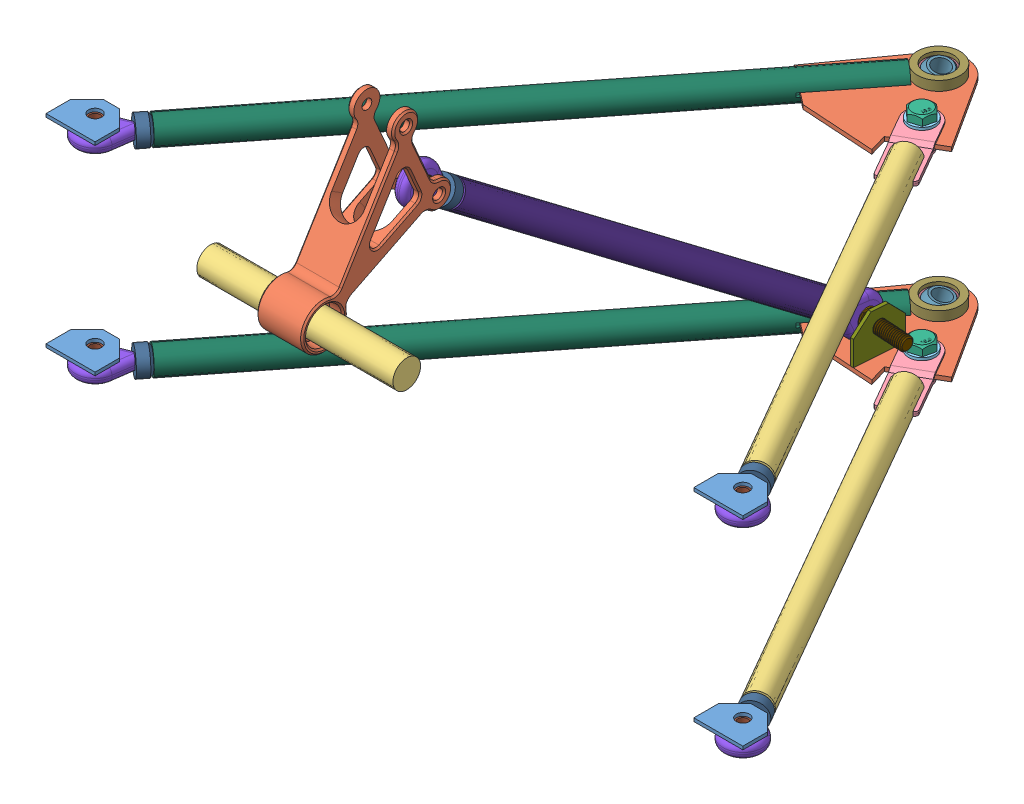
SolidWorks assembly Control Arms, Pushord, Bellcrank V2, configuration Default. Lengths in mm.
Overall size (449.35 294.9 454.01).
66 component instances, 21 part files, 26 mates.
Components (placement in the parent):
- frame connectors-10: frame connectors [Default] at (-357.6393 7.7366 39.1204) size (30 2 25)
- frame connectors-11: frame connectors [Default] at (38.6473 7.7366 39.1204) size (30 2 25)
- Upper Control Arm Assembly-1: Upper Control Arm Assembly [Default] at (-132.0035 -126.1112 -251.3303) x (0.997989 0.000512 0.063393) z (-0.063395 0.008067 0.997956) size (428.86 42.68 337.97) (flexible)
  - Front Control Arm Plate-1: Front Control Arm Plate [Default] at origin size (91 2.5 76.52)
  - Rear Upper Control Arm-2: Rear Upper Control Arm [Default] at (105.6055 0 154.4308) x (-0.554844 0 -0.831954) z (0.831954 0 -0.554844) size (250 16 16)
  - Control Arm Link Plate-1: Control Arm Link Plate [Default] at (31.8652 1.25 43.6848) x (-0.554844 0 -0.831954) z (0.831954 0 -0.554844) size (54.1 2.5 20)
  - Control Arm Link Plate-2: Control Arm Link Plate [Default] at (31.8652 -1.25 43.6848) x (-0.554844 0 -0.831954) z (-0.831954 0 0.554844) size (54.1 2.5 20)
  - plain washer normal grade a_iso-1: plain washer normal grade a_iso [Washer ISO 7089 - 8] at (22.4051 2.5 29.5) x (0 -1 0) z (0.774417 0 0.632675) size (1.6 16 16)
  - 94863A205_High-Strength Class 10.9 Steel Hex Head Screw-1: 94863A205_High-Strength Class 10.9 Steel Hex Head Screw [94863A205] at (22.4051 4.1 29.5) x (0.632675 0 -0.774417) z (0 1 0) size (13 16.35 25.89)
  - 94645A111_High-Strength Steel Nylon-Insert Locknut-1: 94645A111_High-Strength Steel Nylon-Insert Locknut [94645A111] at (22.4051 -6.5 29.5) x (-0.775761 0 -0.631027) z (-0.631027 0 0.775761) size (13 8 14.93)
  - Link Insert Assembly-1: Link Insert Assembly [Default] at (151.1806 41.9532 246.62) x (0.831954 0 -0.554844) z (0 -1 0) size (24 54 13.75) (flexible)
    - Link-1: Link [Default] at (13.2343 18.3157 41.9532) size (24 54 13.75)
    - Spherical Bearing Ball-1: Spherical Bearing Ball [Default] at (13.2343 47.8157 41.9532) x (0.00405 -0.006996 0.999967) z (0.475433 -0.879715 -0.00808) size (9 13.75 13.75)
  - Control Arm Insert-1: Control Arm Insert [Default] at (162.0573 0 239.0767) x (-0.831525 0.032128 0.554558) z (0.026729 0.999484 -0.017826) size (16 25 16)
  - 8mm Spehrical Bearing Insert-1: 8mm Spehrical Bearing Insert [Default] at (188.7245 6.4998 279.11) x (0.943262 0.002195 -0.332043) z (-0.33205 0.007779 -0.94323) size (11 9 11)
  - Spherical Bearing Seat-1: Spherical Bearing Seat [Default] at (0 -0.3 0) size (30 15.1 30)
  - Wide Spherical Bearing-1: Wide Spherical Bearing [Default] at (-7.3247 -16.3877 13.3464) x (1 0 0) z (0 1 0) size (28.86 28.32 19.03) (flexible)
    - Wide Bearing Cage-1: Wide Bearing Cage [Default] at (7.3247 13.3464 16.0877) size (22 22 10.5)
    - Wide Ball-1: Wide Ball [Default] at (7.3247 13.3464 16.0877) x (-0.776216 0.626695 0.068867) z (0.18718 0.124767 0.97437) size (19.04 19.04 14)
  - Front Upper Control Arm-1: Front Upper Control Arm [Default] at (-100.6334 0 146.8287) x (0.559193 0 -0.829038) z (0.829038 0 0.559193) size (330 16 16)
  - Link Insert Assembly-2: Link Insert Assembly [Default] at (-191.0018 41.9532 257.1385) x (0.829038 0 0.559193) z (0 -1 0) size (24 54 13.75) (flexible)
    - Link-1: Link [Default] at (13.2343 18.3157 41.9532) size (24 54 13.75)
    - Spherical Bearing Ball-1: Spherical Bearing Ball [Default] at (13.2343 47.8157 41.9532) x (-0.004936 -0.006401 0.999967) z (-0.686878 -0.726729 -0.008042) size (9 13.75 13.75)
  - Control Arm Insert-2: Control Arm Insert [Default] at (-179.8953 0 264.3393) x (-0.82861 0.032128 -0.558904) z (0.026635 0.999484 0.017966) size (16 25 16)
  - 8mm Spehrical Bearing Insert-2: 8mm Spehrical Bearing Insert [Default] at (-206.7649 6.4998 304.2325) x (-0.995552 0.00127 -0.094206) z (-0.094214 -0.007983 0.99552) size (11 9 11)
  - Push Rod Upper Control Arm Bracket-1: Push Rod Upper Control Arm Bracket [Default] at (10.7762 13.75 44.5) x (0 0 1) z (0 -1 0) size (30 2 25)
  - Push Rod Upper Control Arm Bracket-2: Push Rod Upper Control Arm Bracket [Default] at (-11.2238 13.75 44.5) x (0 0 1) z (0 -1 0) size (30 2 25)
- frame connectors-14: frame connectors [Default] at (-357.6393 -114.2634 39.1204) size (30 2 25)
- frame connectors-15: frame connectors [Default] at (38.6473 -114.2634 39.1204) size (30 2 25)
- Lower Control Arm Assembly-4: Lower Control Arm Assembly [Default] at (-132.0035 -4.1112 -251.3303) x (0.997989 0.000512 0.063393) z (-0.063395 0.008067 0.997956) size (428.86 25.91 337.94) (flexible)
  - Front Control Arm Plate-1: Front Control Arm Plate [Default] at origin size (91 2.5 76.52)
  - Rear Upper Control Arm-2: Rear Upper Control Arm [Default] at (105.6055 0 154.4308) x (-0.554844 0 -0.831954) z (0.831954 0 -0.554844) size (250 16 16)
  - Control Arm Link Plate-1: Control Arm Link Plate [Default] at (31.8652 1.25 43.6848) x (-0.554844 0 -0.831954) z (0.831954 0 -0.554844) size (54.1 2.5 20)
  - Control Arm Link Plate-2: Control Arm Link Plate [Default] at (31.8652 -1.25 43.6848) x (-0.554844 0 -0.831954) z (-0.831954 0 0.554844) size (54.1 2.5 20)
  - plain washer normal grade a_iso-1: plain washer normal grade a_iso [Washer ISO 7089 - 8] at (22.4051 2.5 29.5) x (0 -1 0) z (0.774417 0 0.632675) size (1.6 16 16)
  - 94863A205_High-Strength Class 10.9 Steel Hex Head Screw-1: 94863A205_High-Strength Class 10.9 Steel Hex Head Screw [94863A205] at (22.4051 4.1 29.5) x (0.632675 0 -0.774417) z (0 1 0) size (13 16.35 25.89)
  - 94645A111_High-Strength Steel Nylon-Insert Locknut-1: 94645A111_High-Strength Steel Nylon-Insert Locknut [94645A111] at (22.4051 -6.5 29.5) x (-0.783807 0 -0.621005) z (-0.621005 0 0.783807) size (13 8 14.93)
  - Link Insert Assembly-1: Link Insert Assembly [Default] at (151.1806 41.9532 246.62) x (0.831954 0 -0.554844) z (0 -1 0) size (24 54 13.75) (flexible)
    - Link-1: Link [Default] at (13.2343 18.3157 41.9532) size (24 54 13.75)
    - Spherical Bearing Ball-1: Spherical Bearing Ball [Default] at (13.2343 47.8157 41.9532) x (0.00405 -0.006996 0.999967) z (-0.223184 0.974746 0.007723) size (9 13.75 13.75)
  - Control Arm Insert-1: Control Arm Insert [Default] at (162.0573 0 239.0767) x (-0.831525 0.032128 0.554558) z (0.026729 0.999484 -0.017826) size (16 25 16)
  - 8mm Spehrical Bearing Insert-1: 8mm Spehrical Bearing Insert [Default] at (188.7245 6.4998 279.11) x (0.571859 -0.006911 0.820323) z (0.820352 0.004193 -0.571843) size (11 9 11)
  - Spherical Bearing Seat-1: Spherical Bearing Seat [Default] at (0 -0.3 0) size (30 15.1 30)
  - Wide Spherical Bearing-1: Wide Spherical Bearing [Default] at (-7.3247 -16.3877 13.3464) x (1 0 0) z (0 1 0) size (28.91 26.49 19.56) (flexible)
    - Wide Bearing Cage-1: Wide Bearing Cage [Default] at (7.3247 13.3464 16.0877) size (22 22 10.5)
    - Wide Ball-1: Wide Ball [Default] at (7.3247 13.3464 16.0877) x (-0.806936 0.559749 0.188507) z (0.224846 -0.004005 0.974386) size (19.04 19.04 14)
  - Front Upper Control Arm-1: Front Upper Control Arm [Default] at (-100.6334 0 146.8287) x (0.559193 0 -0.829038) z (0.829038 0 0.559193) size (330 16 16)
  - Link Insert Assembly-2: Link Insert Assembly [Default] at (-191.0018 41.9532 257.1385) x (0.829038 0 0.559193) z (0 -1 0) size (24 54 13.75) (flexible)
    - Link-1: Link [Default] at (13.2343 18.3157 41.9532) size (24 54 13.75)
    - Spherical Bearing Ball-1: Spherical Bearing Ball [Default] at (13.2343 47.8157 41.9532) x (-0.004936 -0.006401 0.999967) z (-0.747013 -0.664762 -0.007943) size (9 13.75 13.75)
  - Control Arm Insert-2: Control Arm Insert [Default] at (-179.8953 0 264.3393) x (-0.82861 0.032128 -0.558904) z (0.026635 0.999484 0.017966) size (16 25 16)
  - 8mm Spehrical Bearing Insert-2: 8mm Spehrical Bearing Insert [Default] at (-206.7649 6.4998 304.2325) x (-0.997272 0.001106 -0.0738) z (-0.073807 -0.008007 0.99724) size (11 9 11)
- Front Push Rod Assembly-1: Front Push Rod Assembly [Default] at (-340.7218 -89.8728 119.5451) x (-0.000011 -0.603333 -0.797489) z (1 -0.000019 0) size (363.6 24 20.9) (flexible)
  - Front Push Rod-1: Front Push Rod [Default] at (102.5362 181.4229 205.1752) size (290 16 16)
  - Control Arm Insert-1: Control Arm Insert [Default] at (224.2796 181.4229 205.1752) x (0 -1 0) z (0 0 1) size (16 25 16)
  - Control Arm Insert-2: Control Arm Insert [Default] at (-19.2072 181.4229 205.1752) x (0 -0.381849 0.924225) z (0 -0.924225 -0.381849) size (16 25 16)
  - Link Insert Assembly-1: Link Insert Assembly [Default] at (-19.4481 168.1886 163.222) x (0 1 0) z (0 0 1) size (24 54 13.75)
    - Link-1: Link [Default] at (13.2343 18.3157 41.9532) size (24 54 13.75)
    - Spherical Bearing Ball-1: Spherical Bearing Ball [Default] at (13.2343 47.8157 41.9532) x (0 0 1) z (-0.821758 0.569836 0) size (9 13.75 13.75)
  - Link Insert Assembly-2: Link Insert Assembly [Default] at (224.5204 194.6572 163.222) x (0 -1 0) z (0 0 1) size (24 54 13.75) (flexible)
    - Link-1: Link [Default] at (13.2343 18.3157 41.9532) size (24 54 13.75)
    - Spherical Bearing Ball-1: Spherical Bearing Ball [Default] at (13.2343 47.8157 41.9532) x (0.037823 -0.050875 0.997989) z (0.911135 -0.408374 -0.05535) size (9 13.75 13.75)
- M8 45mm hex bolt-1: M8 45mm hex bolt [91310A132] at (-130.038 -109.5003 -206.7485) x (0.041128 -0.766195 -0.64129) z (-0.997989 -0.000512 -0.063393) size (13 14.81 50.91)
- flat washer narrow_am-1: flat washer narrow_am [B18.22M - Plain washer, 8 mm, narrow] at (-147.0238 -109.509 -207.8275) x (0.997989 0.000512 0.063393) z (-0.063355 -0.027221 0.99762) size (2.3 18.8 18.8)
- Bell Crank-1: Bell Crank [Default] at (-136.5438 60.5574 133.5199) x (0.000017 0.916316 0.400455) z (-0.000008 -0.400455 0.916316) size (76.38 28 99.9)
- FRAME ROD-1: FRAME ROD [Default] at (-132.5438 60.5573 133.5199) x (0.000011 0.607929 0.793992) z (-1 0.000019 0) size (17 17 120)
Mates (geometry in assembly coordinates):
- Concentric18: concentric aligned: cylinder of frame connectors-10 through (-357.6393 8.7366 39.1204) axis (0 -1 0) radius 4; cylinder of frame connectors-14 through (-357.6393 -113.2634 39.1204) axis (0 -1 0) radius 4
- Coincident27: coincident aligned: plane of frame connectors-10 through (-372.6393 8.7366 54.1204) normal (0 0 1); plane of frame connectors-14 through (-372.6393 -113.2634 54.1204) normal (0 0 1)
- Distance2: distance = 120 mm anti-aligned: plane of frame connectors-14 through (-357.6393 -113.2634 39.1204) normal (0 1 0); plane of frame connectors-10 through (-357.6393 6.7366 39.1204) normal (0 -1 0)
- Concentric19: concentric aligned: cylinder of Upper Control Arm Assembly-1/8mm Spehrical Bearing Insert-2 through (-357.6393 -117.2634 39.1204) axis (0 -1 0) radius 3; cylinder of frame connectors-14 through (-357.6393 -113.2634 39.1204) axis (0 -1 0) radius 4
- Coincident29: coincident anti-aligned: plane of Upper Control Arm Assembly-1/8mm Spehrical Bearing Insert-2 through (-352.2076 -115.2634 39.9847) normal (0 1 0); plane of frame connectors-14 through (-357.6393 -115.2634 39.1204) normal (0 -1 0)
- Coincident30: coincident aligned: plane of frame connectors-14 through (-372.6393 -113.2634 54.1204) normal (0 0 1); plane of frame connectors-15 through (23.6473 -113.2634 54.1204) normal (0 0 1)
- Coincident31: coincident aligned: plane of frame connectors-14 through (-357.6393 -113.2634 39.1204) normal (0 1 0); plane of frame connectors-15 through (38.6473 -113.2634 39.1204) normal (0 1 0)
- Concentric21: concentric aligned: cylinder of frame connectors-10 through (-357.6393 8.7366 39.1204) axis (0 -1 0) radius 4; circle of Lower Control Arm Assembly-4/8mm Spehrical Bearing Insert-2
- Coincident33: coincident anti-aligned: plane of frame connectors-10 through (-357.6393 6.7366 39.1204) normal (0 -1 0); plane of Lower Control Arm Assembly-4/8mm Spehrical Bearing Insert-2 through (-352.191 6.7366 39.8732) normal (0 1 0)
- Coincident38: coincident anti-aligned: plane of Upper Control Arm Assembly-1/8mm Spehrical Bearing Insert-1 through (33.354 -115.2634 40.6141) normal (0 1 0); plane of frame connectors-15 through (38.6473 -115.2634 39.1204) normal (0 -1 0)
- Concentric22: concentric aligned: cylinder of Upper Control Arm Assembly-1/8mm Spehrical Bearing Insert-1 through (38.6473 -117.2634 39.1204) axis (0 -1 0) radius 3; cylinder of frame connectors-15 through (38.6473 -113.2634 39.1204) axis (0 -1 0) radius 4
- Coincident39: coincident aligned: plane of frame connectors-10 through (-372.6393 8.7366 54.1204) normal (0 0 1); plane of frame connectors-11 through (23.6473 8.7366 54.1204) normal (0 0 1)
- Coincident40: coincident aligned: plane of frame connectors-10 through (-357.6393 8.7366 39.1204) normal (0 1 0); plane of frame connectors-11 through (38.6473 8.7366 39.1204) normal (0 1 0)
- Concentric23: concentric aligned: cylinder of frame connectors-11 through (38.6473 8.7366 39.1204) axis (0 -1 0) radius 4; cylinder of Lower Control Arm Assembly-4/8mm Spehrical Bearing Insert-1 through (38.6473 4.7366 39.1204) axis (0 -1 0) radius 3
- Coincident41: coincident anti-aligned: plane of frame connectors-11 through (38.6473 6.7366 39.1204) normal (0 -1 0); plane of Lower Control Arm Assembly-4/8mm Spehrical Bearing Insert-1 through (35.7944 6.7366 34.4182) normal (0 1 0)
- Parallel9: parallel aligned: plane of Upper Control Arm Assembly-1/Front Control Arm Plate-1 through (-132.0025 -124.8614 -251.3569) normal (0 0.999967 -0.008083); plane of Lower Control Arm Assembly-4/Front Control Arm Plate-1 through (-132.0025 -2.8614 -251.3569) normal (0 0.999967 -0.008083)
- Concentric24: concentric anti-aligned: cylinder of Upper Control Arm Assembly-1/Push Rod Upper Control Arm Bracket-2 through (-147.0238 -109.509 -207.8275) axis (0.997989 0.000512 0.063393) radius 4; cylinder of flat washer narrow_am-1 through (-181.8786 -109.5269 -210.0415) axis (-0.997989 -0.000512 -0.063393) radius 4.56
- Coincident42: coincident anti-aligned: plane of Upper Control Arm Assembly-1/Push Rod Upper Control Arm Bracket-2 through (-147.0238 -112.0089 -207.8073) normal (-0.997989 -0.000512 -0.063393); plane of flat washer narrow_am-1 through (-147.034 -104.9507 -207.7037) normal (0.997989 0.000512 0.063393)
- Concentric25: concentric anti-aligned: cylinder of Upper Control Arm Assembly-1/Push Rod Upper Control Arm Bracket-2 through (-147.0238 -109.509 -207.8275) axis (0.997989 0.000512 0.063393) radius 4; cylinder of M8 45mm hex bolt-1 through (-149.8481 -109.5105 -208.0069) axis (-0.997989 -0.000512 -0.063393) radius 5.7528
- Coincident43: coincident anti-aligned: plane of M8 45mm hex bolt-1 through (-149.3192 -109.5102 -207.9733) normal (0.997989 0.000512 0.063393); plane of flat washer narrow_am-1 through (-149.3402 -100.1137 -207.7182) normal (-0.997989 -0.000512 -0.063393)
- Concentric26: concentric aligned: cylinder of Front Push Rod Assembly-1/Link Insert Assembly-2/Spherical Bearing Ball-1 through (-142.4099 -109.5066 -207.5344) axis (-0.997989 -0.000512 -0.063393) radius 4; cylinder of M8 45mm hex bolt-1 through (-149.8481 -109.5105 -208.0069) axis (-0.997989 -0.000512 -0.063393) radius 5.7528
- Distance3: distance = 6 mm anti-aligned: plane of Front Push Rod Assembly-1/Link Insert Assembly-2/Spherical Bearing Ball-1 through (-131.2166 -104.9397 -204.3211) normal (0.997989 0.000512 0.063393); plane of Upper Control Arm Assembly-1/Push Rod Upper Control Arm Bracket-1 through (-125.0681 -111.9977 -206.4126) normal (-0.997989 -0.000512 -0.063393)
- Concentric28: concentric aligned: cylinder of Front Push Rod Assembly-1/Link Insert Assembly-1/Spherical Bearing Ball-1 through (-142.4199 95.3889 63.729) axis (-1 0.000019 0) radius 4; cylinder of Bell Crank-1 through (-122.5432 95.3885 63.729) axis (-1 0.000019 0) radius 3
- Distance4: distance = 7 mm anti-aligned: plane of Front Push Rod Assembly-1/Link Insert Assembly-1/Link-1 through (-139.5432 95.3888 63.729) normal (-1 0.000019 0); plane of Bell Crank-1 through (-146.543 103.2757 25.7053) normal (1 -0.000019 0)
- Concentric34: concentric anti-aligned: cylinder of Bell Crank-1 through (-122.5438 60.5572 133.5199) axis (-1 0.000019 0) radius 8.5; cylinder of FRAME ROD-1 through (-192.5438 60.5585 133.5199) axis (1 -0.000019 0) radius 8.5
- Distance5: distance = 50 mm aligned: plane of Bell Crank-1 through (-122.5438 60.5572 133.5199) normal (1 -0.000019 0); plane of FRAME ROD-1 through (-72.5438 60.5562 133.5199) normal (1 -0.000019 0)
